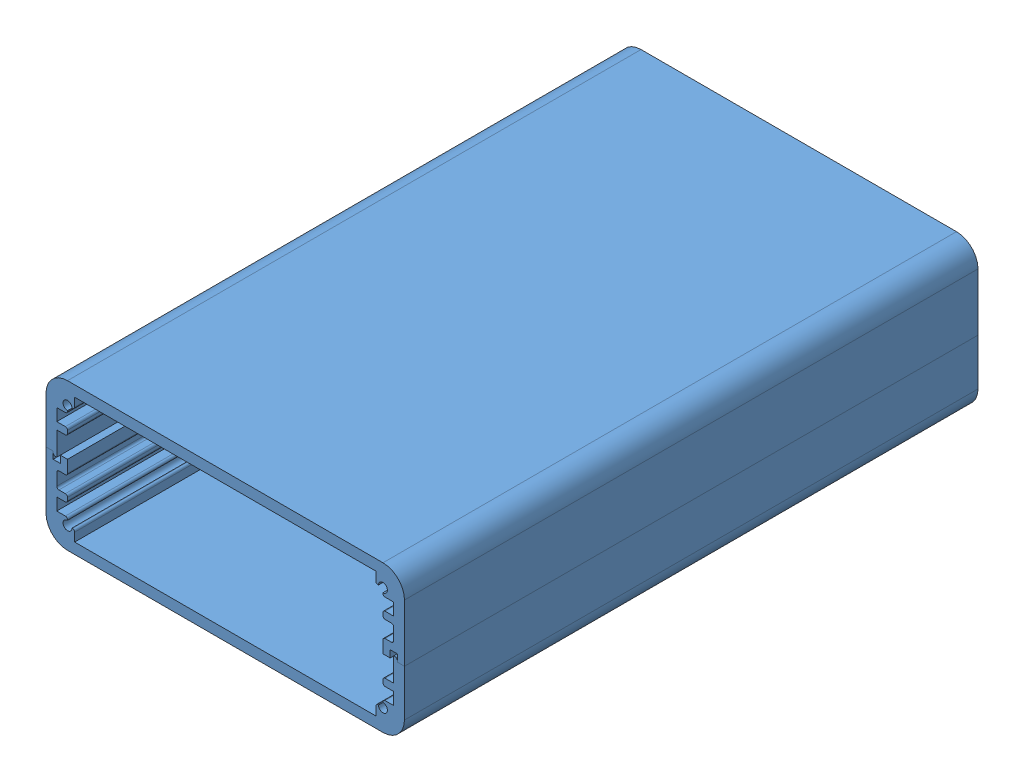
SolidWorks assembly Assem2, configuration Default. Lengths in mm.
Overall size (50 20.5 80).
2 component instances, 1 part files, 5 mates.
Components (placement in the parent):
- case-1: case [Default] at (-9.9049 -10.2865 -40) size (50 11 80)
- case-2: case [Default] at (1.6835 8.41 -40) x (-1 0 0) z (0 0 1) size (50 11 80)
Mates (geometry in assembly coordinates):
- Coincident1: coincident: plane of case-1 through (-27.6107 -2.4882 40) normal (1 0 0); plane of case-2 through (-27.6107 2.6118 36.0792) normal (1 0 0)
- Coincident3: coincident: plane of case-1 through (-27.6107 -2.4882 40) normal (1 0 0); plane of case-2 through (-27.6107 2.6118 36.0792) normal (1 0 0)
- Parallel2: parallel: plane of case-1 through (19.3893 -4.4882 40) normal (-1 0 0); plane of case-2 through (19.3893 0.6118 40) normal (-1 0 0)
- Coincident6: coincident: plane of case-1 through (19.8933 -1.6882 40) normal (0 1 0); plane of case-2 through (20.8893 -1.6882 40) normal (0 -1 0)
- Coincident7: coincident aligned: plane of case-1 through (-26.1107 -8.1882 40) normal (0 0 1); plane of case-2 through (17.8893 6.3118 40) normal (0 0 1)
